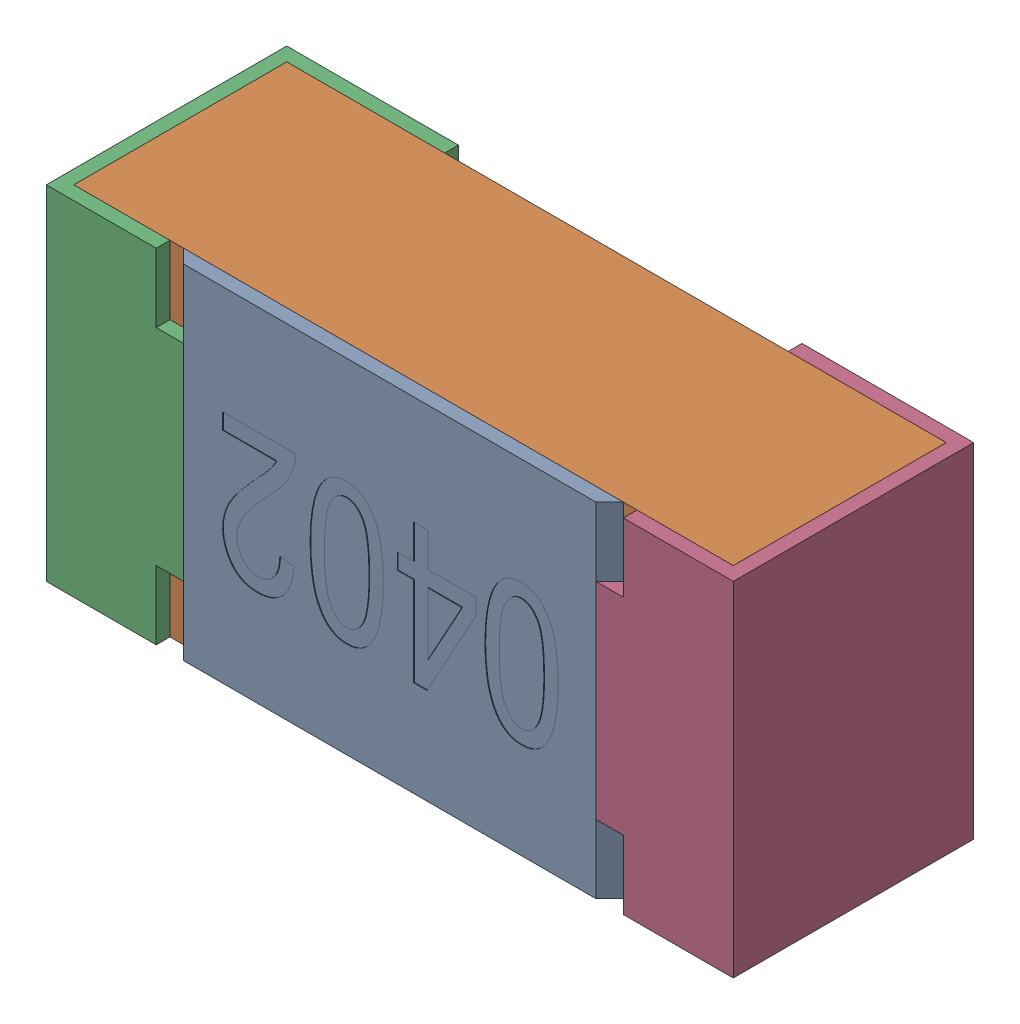
SolidWorks assembly R19, configuration Standard. Lengths in mm.
Overall size (1 0.5 0.35).
5 component instances, 4 part files, 0 mates.
Components (placement in the parent):
- R19-subassembly-1-1: R19-subassembly-1 [Standard] at (-12.8001 -16.8 0) x (-1 0 0) z (0 0 1) size (1 0.5 0.35)
  - User Library-R_0402-1: User Library-R_0402 [Standard] at origin size (0.64 0.5 0.02)
  - User Library-R_0402-1-1: User Library-R_0402-1 [Standard] at origin size (0.96 0.5 0.31)
  - User Library-R_0402-2-1: User Library-R_0402-2 [Standard] at origin size (0.25 0.5 0.35)
  - User Library-R_0402-3-1: User Library-R_0402-3 [Standard] at origin size (0.25 0.5 0.35)
